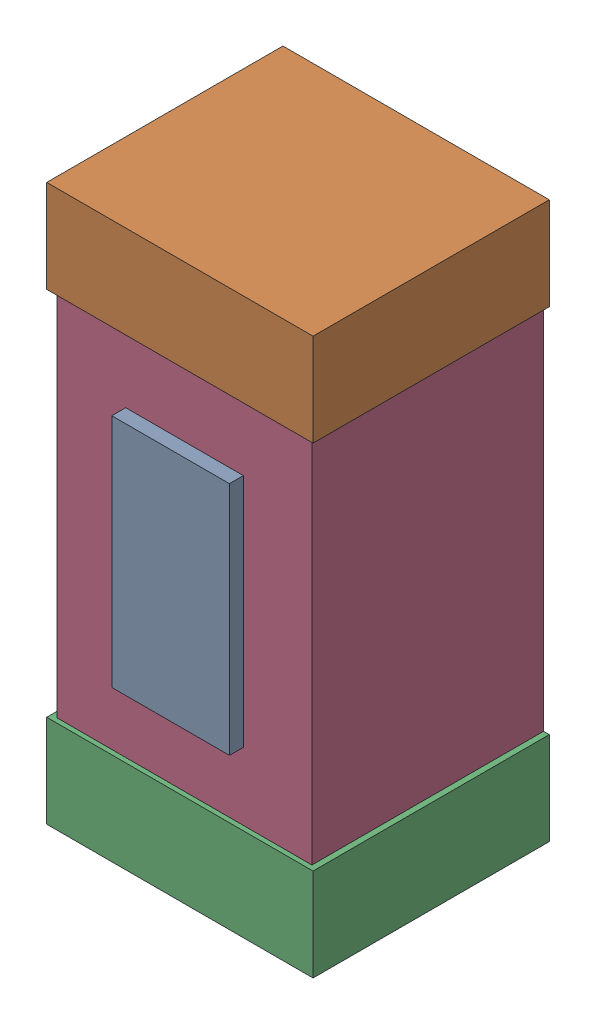
SolidWorks assembly SATA_2, configuration Default. Lengths in mm.
Overall size (0.58 1.2 0.53).
8 component instances, 3 part files, 0 mates.
Components (placement in the parent):
- 402660368-1: 402660368 [Default] at (129.54 5.715 0) size (0.25 0.51 0.53)
  - Extruded_12-1: Extruded_12 [Default] at origin size (0.25 0.51 0.53)
- 402663952-1: 402663952 [Default] at (129.54 6.215 0) size (0.58 0.2 0.51)
  - Extruded_13-1: Extruded_13 [Default] at origin size (0.58 0.2 0.51)
- 402663952-2: 402663952 [Default] at (129.54 5.215 0) size (0.58 0.2 0.51)
  - Extruded_13-1: Extruded_13 [Default] at origin size (0.58 0.2 0.51)
- 402663824-1: 402663824 [Default] at (129.54 5.715 0) size (0.55 1.15 0.5)
  - Extruded_14-1: Extruded_14 [Default] at origin size (0.55 1.15 0.5)
